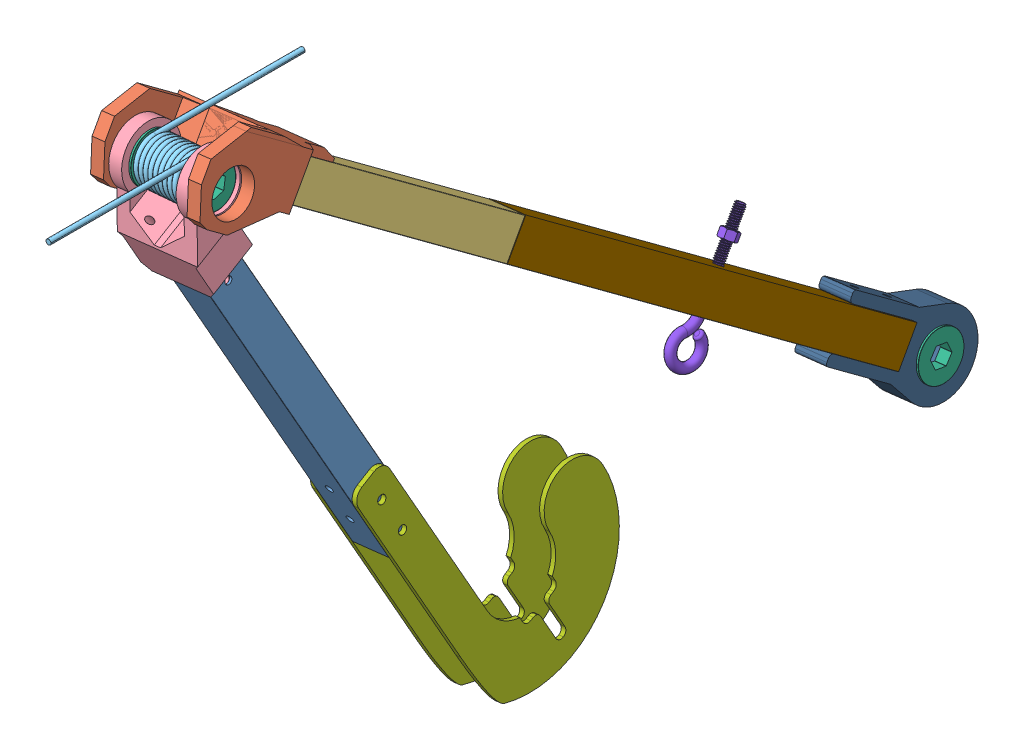
SolidWorks assembly ClimberRev2 back, configuration Default. Lengths in mm.
Overall size (102.13 434.52 611.21).
15 component instances, 10 part files, 30 mates.
Components (placement in the parent):
- 1x1x20 box extrusion for climber-4: 1x1x20 box extrusion for climber [Default] at (3.825 -50.3582 -245.089) x (0.993572 0.113203 0) z (0.10067 -0.883567 -0.457357) size (25.4 25.4 254)
- Climber Insert Rev3 Outer-3: Climber Insert Rev3 Outer [Default] at (4.2736 -50.8774 -314.6587) x (0.993572 0.113203 0) z (0.066232 -0.581307 -0.810985) size (75.39 53.74 112.86)
- 1x1x20 box extrusion for climber upper-3: 1x1x20 box extrusion for climber upper [Default] at (25.7469 -43.0175 -269.2161) x (-0.993572 -0.113203 0) z (0.066232 -0.581307 -0.810985) size (25.4 25.4 508)
- Climber Insert Rev3 Inner-1: Climber Insert Rev3 Inner [Default] at (20.8475 -99.1304 -258.1921) x (0.993572 0.113203 0) z (-0.10067 0.883567 0.457357) size (55.21 53.46 97.31)
- 9271K126_Torsion Spring.step-2: 9271K126_Torsion Spring.step [Default] at (27.3298 -21.5529 -237.4141) x (-0.99171 -0.121767 -0.041038) z (-0.040732 -0.005001 0.999158) size (42.85 30.25 203.17)
- am-2986 FR8ZZ Hex Bearing.step-1: am-2986 FR8ZZ Hex Bearing.step [Default] at (-12.7535 -26.1049 -238.3356) x (0 0 -1) z (0.993572 0.113203 0) size (31.12 31.12 7.93)
- am-2986 FR8ZZ Hex Bearing.step-2: am-2986 FR8ZZ Hex Bearing.step [Default] at (37.1602 -20.418 -238.3356) x (0.109137 -0.957884 0.265609) z (-0.993572 -0.113203 0) size (31.12 31.12 7.93)
- Candy cane claw-1: Candy cane claw [Default] at (48.2703 -230.0971 -332.3609) x (0.051774 -0.454417 0.889283) z (0.993572 0.113203 0) size (119.68 195.58 3.78)
- Candy cane claw-2: Candy cane claw [Default] at (19.8789 -233.3319 -332.3609) x (0.051774 -0.454417 0.889283) z (0.993572 0.113203 0) size (119.68 195.58 3.78)
- 9489T21_Routing Eyebolt with Nut - Not for Lifting-1: 9489T21_Routing Eyebolt with Nut - Not for Lifting [9489T21] at (40.9191 -274.3463 -556.3019) x (0.205015 -0.559666 -0.802958) z (-0.974444 -0.193664 -0.113815) size (25.4 89.57 11)
- Climber Cap v1.step-1: Climber Cap v1.step [Default] at (78.9116 -276.2007 -555.6809) x (0.993572 0.113203 0) z (0.066232 -0.581307 -0.810985) size (25.4 52.98 357.78)
  - 6546K531_Multipurpose 6061 Aluminum Rectangular Tube.step-1: 6546K531_Multipurpose 6061 Aluminum Rectangular Tube.step [Default] at (-37.1384 -36.4845 -15.0406) size (25.4 25.4 304.8) (hidden)
  - Climber Cap.step-1: Climber Cap.step [Default] at origin size (21.82 52.98 103.78)
- am-2986 FR8ZZ Hex Bearing.step-3: am-2986 FR8ZZ Hex Bearing.step [Default] at (53.7957 -345.7641 -709.9041) x (0.017763 -0.155905 -0.987612) z (0.993572 0.113203 0) size (31.12 31.12 7.93)
- am-2986 FR8ZZ Hex Bearing.step-4: am-2986 FR8ZZ Hex Bearing.step [Default] at (44.8354 -346.785 -709.9041) x (-0.105704 0.927752 0.357915) z (-0.993572 -0.113203 0) size (31.12 31.12 7.93)
Mates (geometry in assembly coordinates):
- Coincident18: coincident anti-aligned: plane of Climber Insert Rev3 Outer-3 through (6.6456 -49.2587 -312.8015) normal (-0.091806 0.805771 -0.585067); plane of 1x1x20 box extrusion for climber-3 through (55.0354 -277.6417 -596.9431) normal (-0.091806 0.805771 -0.585067)
- Coincident19: coincident anti-aligned: plane of Climber Insert Rev3 Outer-3 through (30.2309 -64.3082 -300.088) normal (0.993572 0.113203 0); plane of 1x1x20 box extrusion for climber-3 through (52.995 -259.7335 -609.9463) normal (-0.993572 -0.113203 0)
- Coincident20: coincident anti-aligned: plane of Climber Insert Rev3 Outer-3 through (5.9913 -43.5158 -267.6486) normal (0.066232 -0.581307 -0.810985); plane of 1x1x20 box extrusion for climber-3 through (56.4827 -278.5653 -596.1629) normal (0.066232 -0.581307 -0.810985)
- Coincident21: coincident anti-aligned: plane of Climber Insert Rev3 Outer-3 through (3.6193 -45.1346 -269.5057) normal (0.066232 -0.581307 -0.810985); plane of 1x1x20 box extrusion for climber upper-3 through (27.1942 -43.941 -268.436) normal (-0.066232 0.581307 0.810985)
- Coincident22: coincident anti-aligned: plane of Climber Insert Rev3 Outer-3 through (6.2685 -68.3868 -301.9451) normal (-0.993572 -0.113203 0); plane of 1x1x20 box extrusion for climber upper-3 through (35.27 -322.9289 -694.1994) normal (0.993572 0.113203 0)
- Coincident23: coincident anti-aligned: plane of Climber Insert Rev3 Outer-3 through (4.2736 -50.8774 -314.6587) normal (-0.091806 0.805771 -0.585067); plane of 1x1x20 box extrusion for climber upper-3 through (57.3521 -320.4129 -694.1994) normal (0.091806 -0.805771 0.585067)
- Coincident24: coincident anti-aligned: plane of 1x1x20 box extrusion for climber-4 through (52.628 -282.3676 -341.4934) normal (-0.993572 -0.113203 0); plane of Climber Insert Rev3 Inner-1 through (25.9361 -48.0962 -244.592) normal (0.993572 0.113203 0)
- Coincident25: coincident anti-aligned: plane of 1x1x20 box extrusion for climber-4 through (2.4311 -49.9032 -246.2748) normal (-0.10067 0.883567 0.457357); plane of Climber Insert Rev3 Inner-1 through (15.7335 -54.2453 -234.9584) normal (0.10067 -0.883567 -0.457357)
- Coincident27: coincident anti-aligned: plane of 1x1x20 box extrusion for climber-4 through (30.5458 -284.8835 -341.4934) normal (-0.051774 0.454417 -0.889283); plane of Climber Insert Rev3 Inner-1 through (27.0579 -57.9417 -225.3247) normal (0.051774 -0.454417 0.889283)
- Concentric2: concentric aligned: circle of Climber Insert Rev3 Outer-3; circle of Climber Insert Rev3 Inner-1
- Distance2: distance = 1.27 mm anti-aligned: plane of Climber Insert Rev3 Inner-1 through (-11.9497 -55.126 -233.7967) normal (-0.993572 -0.113203 0); plane of Climber Insert Rev3 Outer-3 through (-13.4815 -52.9003 -314.6587) normal (0.993572 0.113203 0)
- Concentric3: concentric anti-aligned: cylinder of Climber Insert Rev3 Outer-3 through (-60.9027 -31.5908 -238.3356) axis (0.993572 0.113203 0) radius 14.5; cylinder of am-2986 FR8ZZ Hex Bearing.step-1 through (-4.8771 -25.2075 -238.3356) axis (-0.993572 -0.113203 0) radius 14.2875
- Coincident28: coincident anti-aligned: plane of Climber Insert Rev3 Inner-1 through (2.2528 -101.249 -258.1921) normal (0.993572 0.113203 0); plane of am-2986 FR8ZZ Hex Bearing.step-1 through (-6.3913 -25.38 -252.3056) normal (-0.993572 -0.113203 0)
- Concentric4: concentric aligned: cylinder of Climber Insert Rev3 Inner-1 through (30.7981 -21.1428 -238.3356) axis (0.993572 0.113203 0) radius 14.5; cylinder of am-2986 FR8ZZ Hex Bearing.step-2 through (29.2839 -21.3154 -238.3356) axis (0.993572 0.113203 0) radius 14.2875
- Coincident29: coincident anti-aligned: plane of Climber Insert Rev3 Inner-1 through (39.4422 -97.0118 -258.1921) normal (-0.993572 -0.113203 0); plane of am-2986 FR8ZZ Hex Bearing.step-2 through (32.3227 -34.5245 -234.625) normal (0.993572 0.113203 0)
- Coincident30: coincident anti-aligned: plane of 1x1x20 box extrusion for climber-4 through (54.2743 -282.7939 -340.3075) normal (0.993572 0.113203 0); plane of Candy cane claw-1 through (59.3283 -327.1527 -420.1078) normal (-0.993572 -0.113203 0)
- Coincident31: coincident aligned: plane of 1x1x20 box extrusion for climber-4 through (29.3031 -285.7559 -340.0816) normal (0.051774 -0.454417 0.889283); plane of Candy cane claw-1 through (53.0951 -244.3974 -320.333) normal (0.051774 -0.454417 0.889283)
- Distance3: distance = 50.8 mm anti-aligned: plane of Candy cane claw-1 through (51.4075 -229.5851 -332.6593) normal (-0.10067 0.883567 0.457357); plane of 1x1x20 box extrusion for climber-4 through (28.0012 -274.3291 -362.4435) normal (0.10067 -0.883567 -0.457357)
- Coincident33: coincident anti-aligned: plane of 1x1x20 box extrusion for climber-4 through (27.7488 -274.3579 -362.4435) normal (-0.993572 -0.113203 0); plane of Candy cane claw-2 through (34.0916 -330.028 -420.1078) normal (0.993572 0.113203 0)
- Coincident34: coincident: plane of 1x1x20 box extrusion for climber-4 through (29.3031 -285.7559 -340.0816) normal (0.051774 -0.454417 0.889283); line of Candy cane claw-2 through (24.7038 -247.6322 -320.333) axis (0.10067 -0.883567 -0.457357)
- Concentric5: concentric aligned: cylinder of Candy cane claw-1 through (62.4829 -326.7932 -420.1078) axis (-0.993572 -0.113203 0) radius 68.58; cylinder of Candy cane claw-2 through (34.0916 -330.028 -420.1078) axis (-0.993572 -0.113203 0) radius 68.58
- Coincident35: coincident: circle of 1x1x20 box extrusion for climber upper-3; circle of 9489T21_Routing Eyebolt with Nut - Not for Lifting-1
- Coincident37: coincident anti-aligned: plane of 1x1x20 box extrusion for climber upper-3 through (57.3521 -320.4129 -694.1994) normal (-0.993572 -0.113203 0); plane of Climber Cap v1.step-1/Climber Cap.step-1 through (58.4756 -330.2741 -689.3051) normal (0.993572 0.113203 0)
- Coincident38: coincident anti-aligned: plane of 1x1x20 box extrusion for climber upper-3 through (57.3521 -320.4129 -694.1994) normal (0.091806 -0.805771 0.585067); plane of Climber Cap v1.step-1/Climber Cap.step-1 through (35.7171 -323.3196 -694.8077) normal (-0.091806 0.805771 -0.585067)
- Coincident39: coincident anti-aligned: line of 1x1x20 box extrusion for climber upper-3 through (57.3521 -320.4129 -694.1994) axis (-0.993572 -0.113203 0); line of Climber Cap v1.step-1/Climber Cap.step-1 through (35.6674 -322.8836 -694.1994) axis (0.993572 0.113203 0)
- Concentric6: concentric anti-aligned: cylinder of Climber Cap v1.step-1/Climber Cap.step-1 through (38.4732 -347.5099 -709.9041) axis (0.993572 0.113203 0) radius 14.4875; cylinder of am-2986 FR8ZZ Hex Bearing.step-3 through (61.6721 -344.8667 -709.9041) axis (-0.993572 -0.113203 0) radius 14.2875
- Concentric7: concentric aligned: cylinder of Climber Cap v1.step-1/Climber Cap.step-1 through (38.4732 -347.5099 -709.9041) axis (0.993572 0.113203 0) radius 14.4875; cylinder of am-2986 FR8ZZ Hex Bearing.step-4 through (36.959 -347.6824 -709.9041) axis (0.993572 0.113203 0) radius 14.2875
- Coincident40: coincident anti-aligned: plane of Climber Cap v1.step-1/Climber Cap.step-1 through (36.7909 -332.7447 -689.3051) normal (-0.993572 -0.113203 0); plane of am-2986 FR8ZZ Hex Bearing.step-4 through (36.9965 -334.5492 -704.904) normal (0.993572 0.113203 0)
- Coincident41: coincident anti-aligned: plane of Climber Cap v1.step-1/Climber Cap.step-1 through (58.4756 -330.2741 -689.3051) normal (0.993572 0.113203 0); plane of am-2986 FR8ZZ Hex Bearing.step-3 through (60.4061 -347.2173 -723.701) normal (-0.993572 -0.113203 0)
- Coincident42: coincident aligned: plane of am-2986 FR8ZZ Hex Bearing.step-3 through (61.0273 -339.2073 -714.5212) normal (0.040517 -0.355614 0.933754); plane of am-2986 FR8ZZ Hex Bearing.step-4 through (37.0892 -348.8256 -717.1456) normal (0.040517 -0.355614 0.933754)
